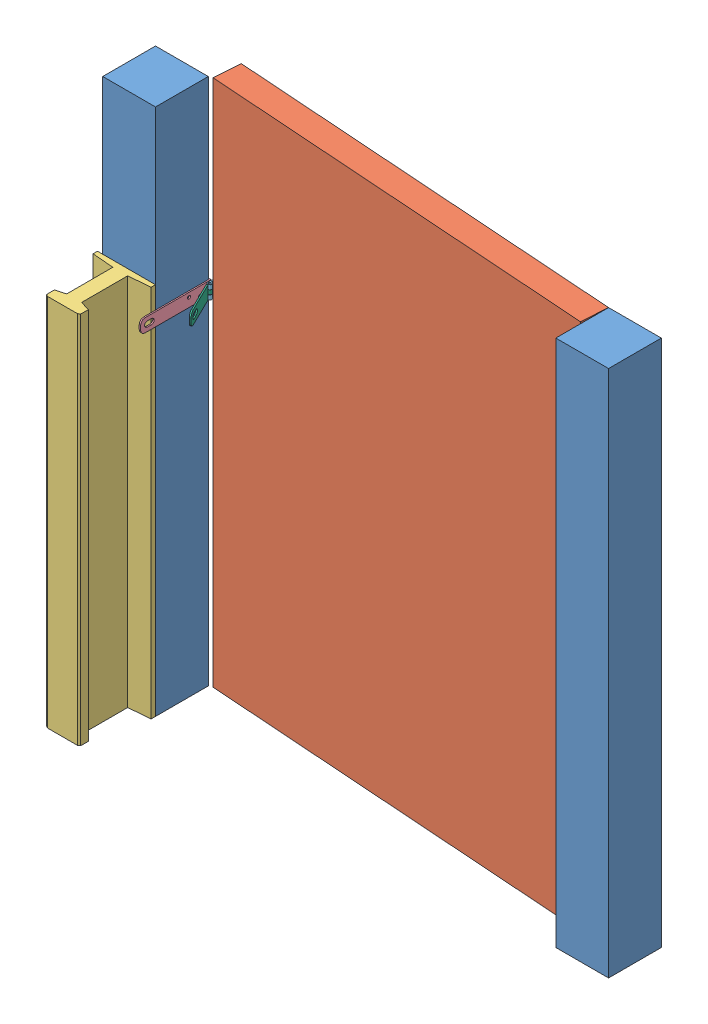
SolidWorks assembly СбКалитка, configuration По умолчанию. Lengths in mm.
Overall size (1162 1200 331.82).
8 component instances, 6 part files, 16 mates.
Components (placement in the parent):
- Брус-1: Брус [По умолчанию] at origin size (120 1200 120)
- Калитка-1: Калитка [По умолчанию] at (132.1924 0 -182.7808) x (-0.069756 0 0.997564) z (-0.997564 0 -0.069756) size (60 1200 900)
- Рельс-1: Рельс [По умолчанию] at (54 0 0) x (0 1 0) z (1 0 0) size (850 145.71 132)
- Брус-2: Брус [По умолчанию] at (1030 0 -120) x (0 0 1) z (-1 0 0) size (120 1200 120)
- Скоба2-1: Скоба2 [По умолчанию] at (123 770 -123) x (-1 0 0) z (0 0 -1) size (70 30 160)
- СБСкобаК-1: СБСкобаК [По умолчанию] at (129.4089 800 -185.9828) x (0.997564 0 0.069756) z (0.069756 0 -0.997564) size (71.85 30 150.33)
  - Скоба-1: Скоба [По умолчанию] at origin size (70.2 30 75.5)
  - Петля-1: Петля [По умолчанию] at (47.6742 0 -148.7263) x (-0.5 0 0.866025) z (-0.866025 0 -0.5) size (93.5 30 9)
Mates (geometry in assembly coordinates):
- Совпадение1: coordinate: point of Брус-1; point of assembly
- Совпадение2: coincident aligned: plane of Брус-1 through (0 1200 0) normal (0 0 1); plane of Брус-2 through (1030 1200 0) normal (0 0 1)
- Совпадение4: coincident aligned: plane of Брус-1 through (0 1200 0) normal (0 1 0); plane of Брус-2 through (1030 1200 -120) normal (0 1 0)
- Совпадение5: coincident anti-aligned: line of Калитка-1 through (1030 0 -120) axis (0 1 0); line of Брус-2 through (1030 1200 -120) axis (0 -1 0)
- Совпадение6: coincident aligned: plane of Калитка-1 through (130 1200 -60) normal (0 1 0); plane of Брус-2 through (1030 1200 -120) normal (0 1 0)
- Совпадение7: coincident anti-aligned: plane of Брус-1 through (0 1200 0) normal (0 0 1); plane of Рельс-1 through (120 850 0) normal (0 0 -1)
- Расстояние2: distance = 910 mm anti-aligned: plane of Брус-2 through (1030 1200 -120) normal (-1 0 0); plane of Брус-1 through (120 1200 0) normal (1 0 0)
- Совпадение19: coincident aligned: plane of Брус-1 through (120 1200 0) normal (1 0 0); plane of Рельс-1 through (120 850 0) normal (1 0 0)
- Совпадение11: coincident aligned: plane of Брус-1 through (0 0 0) normal (0 -1 0); plane of Рельс-1 through (54 0 0) normal (0 -1 0)
- Угол1: planar angle = 3.211406 rad anti-aligned: plane of Брус-2 through (1030 1200 -120) normal (0 0 -1); plane of Калитка-1 through (132.1924 0 -182.7808) normal (0.069756 0 -0.997564)
- Совпадение20: coincident anti-aligned: plane of Брус-1 through (0 1200 -120) normal (0 0 -1); plane of Скоба2-1 through (123 800 -120) normal (0 0 1)
- Совпадение21: coincident anti-aligned: plane of Брус-1 through (120 1200 0) normal (1 0 0); plane of Скоба2-1 through (120 800 -123) normal (-1 0 0)
- Расстояние6: distance = 400 mm aligned: plane of Скоба2-1 through (123 800 -123) normal (0 1 0); plane of Брус-1 through (0 1200 0) normal (0 1 0)
- Совпадение22: coincident anti-aligned: plane of Калитка-1 through (130 0 -120) normal (0 0 -1); plane of СБСкобаК-1/Скоба-1 through (127 770 -120) normal (0 0 1)
- Совпадение23: coincident anti-aligned: plane of Калитка-1 through (130 0 -60) normal (-1 0 0); plane of СБСкобаК-1/Скоба-1 through (130 770 -123) normal (1 0 0)
- Расстояние7: distance = 400 mm aligned: plane of СБСкобаК-1/Скоба-1 through (129.4089 800 -185.9828) normal (0 1 0); plane of Калитка-1 through (128.007 1200 -122.927) normal (0 1 0)
